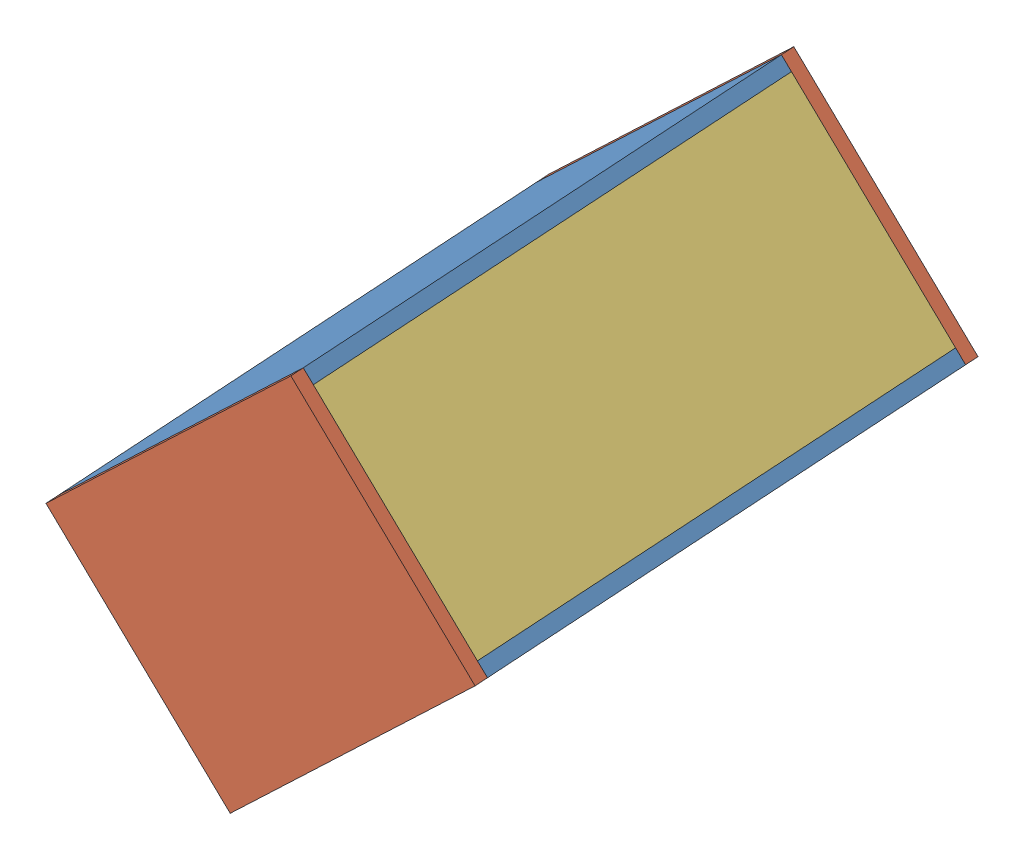
SolidWorks assembly Assemblage1, configuration Défaut. Lengths in mm.
Overall size (481.08 474.5 649.55).
6 component instances, 3 part files, 15 mates.
Components (placement in the parent):
- Pièce2-1: Pièce2 [Défaut] at (-118.3821 734.0433 529.6534) x (-0.104012 -0.044477 -0.993581) z (0.682707 -0.729662 -0.038805) size (579 318 15)
- Pièce3-1: Pièce3 [Défaut] at (-357.6687 897.3359 -50.4444) x (0.682707 -0.729662 -0.038805) z (0.104012 0.044477 0.993581) size (275 318 15)
- Pièce1-2: Pièce1 [Défaut] at (-285.6452 912.8104 539.1607) x (0.682707 -0.729662 -0.038805) z (0.723252 0.68236 -0.106258) size (245 579 15)
- Pièce1-3: Pièce1 [Défaut] at (-66.4999 1119.5656 506.9645) x (0.682707 -0.729662 -0.038805) z (0.723252 0.68236 -0.106258) size (245 579 15)
- Pièce2-2: Pièce2 [Défaut] at (-126.1144 1114.9936 -69.3308) x (0.104012 0.044477 0.993581) z (0.682707 -0.729662 -0.038805) size (579 318 15)
- Pièce3-2: Pièce3 [Défaut] at (-295.8858 923.7553 539.7428) x (0.682707 -0.729662 -0.038805) z (0.104012 0.044477 0.993581) size (275 318 15)
Mates (geometry in assembly coordinates):
- Coïncidente3: coincident aligned: line of Pièce2-2 through (-65.8917 1140.7459 505.9527) axis (-0.723252 -0.68236 0.106258); line of Pièce3-2 through (-65.8917 1140.7459 505.9527) axis (-0.723252 -0.68236 0.106258)
- Coïncidente4: coincident aligned: plane of Pièce2-2 through (-345.8679 887.0581 -36.1228) normal (-0.723252 -0.68236 0.106258); plane of Pièce3-2 through (-294.3256 924.4225 554.6465) normal (-0.723252 -0.68236 0.106258)
- Coïncidente5: coincident aligned: line of Pièce2-2 through (-55.6511 1129.801 505.3706) axis (-0.682707 0.729662 0.038805); line of Pièce3-2 through (121.8526 940.089 495.2813) axis (-0.682707 0.729662 0.038805)
- Coïncidente7: coincident aligned: plane of Pièce2-1 through (121.8526 940.089 495.2813) normal (0.723252 0.68236 -0.106258); plane of Pièce3-2 through (-64.3315 1141.4131 520.8564) normal (0.723252 0.68236 -0.106258)
- Coïncidente8: coincident anti-aligned: line of Pièce2-1 through (121.8526 940.089 495.2813) axis (-0.723252 -0.68236 0.106258); line of Pièce3-2 through (-108.1415 723.0984 529.0714) axis (0.723252 0.68236 -0.106258)
- Coïncidente9: coincident aligned: line of Pièce2-1 through (121.8526 940.089 495.2813) axis (-0.682707 0.729662 0.038805); line of Pièce3-2 through (121.8526 940.089 495.2813) axis (-0.682707 0.729662 0.038805)
- Coïncidente10: coincident anti-aligned: line of Pièce3-1 through (-126.1144 1114.9936 -69.3308) axis (-0.723252 -0.68236 0.106258); line of Pièce2-2 through (-356.1085 898.003 -35.5407) axis (0.723252 0.68236 -0.106258)
- Parallèle1: parallel aligned: line of Pièce3-1 through (60.0698 913.6695 -94.9059) axis (-0.682707 0.729662 0.038805); line of Pièce2-2 through (-115.8738 1104.0487 -69.9128) axis (-0.682707 0.729662 0.038805)
- Coïncidente13: coincident aligned: plane of Pièce3-1 through (-356.1085 898.003 -35.5407) normal (-0.723252 -0.68236 0.106258); plane of Pièce2-2 through (-345.8679 887.0581 -36.1228) normal (-0.723252 -0.68236 0.106258)
- Coïncidente14: coincident aligned: line of Pièce3-1 through (61.6299 914.3367 -80.0022) axis (-0.682707 0.729662 0.038805); line of Pièce1-3 through (51.3893 925.2816 -79.4201) axis (-0.682707 0.729662 0.038805)
- Coïncidente15: coincident anti-aligned: line of Pièce1-3 through (-55.6511 1129.801 505.3706) axis (0.682707 -0.729662 -0.038805); line of Pièce3-2 through (121.8526 940.089 495.2813) axis (-0.682707 0.729662 0.038805)
- Coïncidente16: coincident aligned: line of Pièce1-3 through (-115.8738 1104.0487 -69.9128) axis (0.104012 0.044477 0.993581); line of Pièce2-2 through (-115.8738 1104.0487 -69.9128) axis (0.104012 0.044477 0.993581)
- Coïncidente17: coincident aligned: line of Pièce2-1 through (-118.3821 734.0433 529.6534) axis (-0.104012 -0.044477 -0.993581); line of Pièce1-2 through (-118.3821 734.0433 529.6534) axis (-0.104012 -0.044477 -0.993581)
- Coïncidente18: coincident anti-aligned: line of Pièce1-2 through (-345.8679 887.0581 -36.1228) axis (0.104012 0.044477 0.993581); line of Pièce2-2 through (-285.6452 912.8104 539.1607) axis (-0.104012 -0.044477 -0.993581)
- Coïncidente19: coincident aligned: line of Pièce1-2 through (-285.6452 912.8104 539.1607) axis (0.682707 -0.729662 -0.038805); line of Pièce3-2 through (-295.8858 923.7553 539.7428) axis (0.682707 -0.729662 -0.038805)
